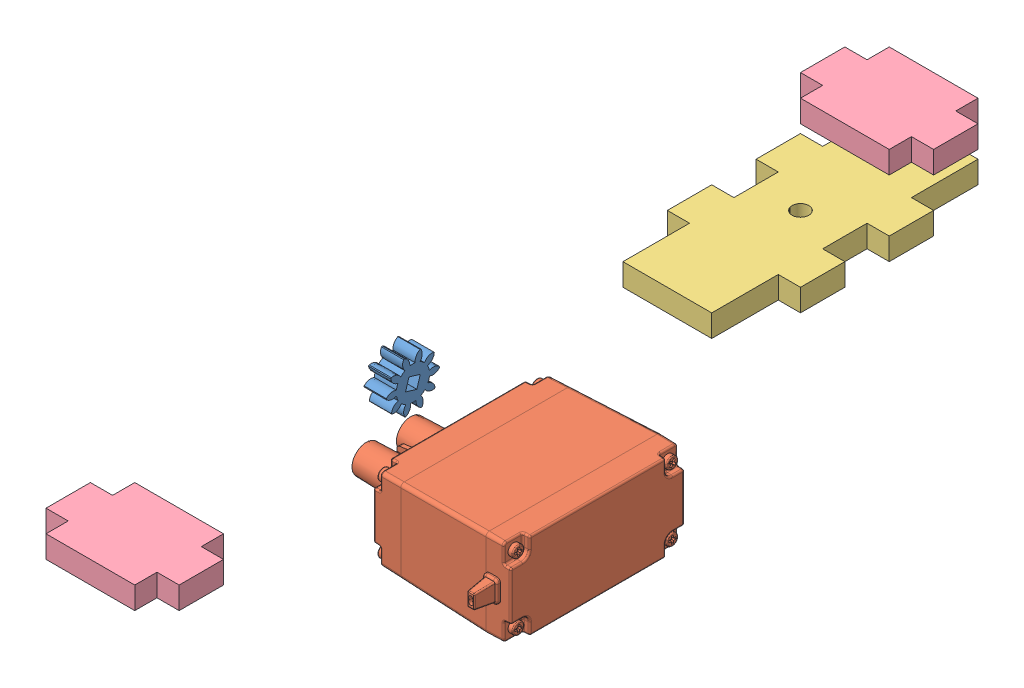
SolidWorks assembly Axis 2, configuration Default. Lengths in mm.
Overall size (105.18 50.55 254).
7 component instances, 5 part files, 17 mates.
Components (placement in the parent):
- spur gear_ai-1: spur gear_ai [Inch - Spur gear 20DP 10T 20PA 0.25"FW ---S10N3.0H2.0L0.1875N] at (-25.5488 56.17 -24.2712) x (1 0 0) z (0 0.958122 -0.28636) size (6.35 14.58 15.24)
- rack spur rectangular_ai-1: rack spur rectangular_ai [Inch - Rack-spur - rectangular 20DP 20PA 0.25"FW 1"PH 10L---SAll] at (-19.1988 24.474 55.3228) x (0 0 -1) z (1 0 0) size (254 26.67 6.35)
- 276-2177-1: 276-2177 [Default] at (40.8761 56.17 1.4288) x (0 0 -1) z (0 -1 0) size (56.4 55.81 25)
- Adapter Plate-1: Adapter Plate [Default] at (-38.2488 18.124 -147.8772) x (0 0 1) z (-1 0 0) size (76.2 6.35 38.1)
- rack spur rectangular_ai-2: rack spur rectangular_ai [Inch - Rack-spur - rectangular 20DP 20PA 0.25"FW 1"PH 10L---SAll] at (-50.9488 24.474 55.3228) x (0 0 -1) z (1 0 0) size (254 26.67 6.35)
- Rack Bridge-3: Rack Bridge [Default] at (-50.9488 33.237 48.9728) x (0 0 1) z (0 1 0) size (25.4 38.1 6.35)
- Rack Bridge-4: Rack Bridge [Default] at (-50.9488 33.237 -166.9272) x (0 0 1) z (0 1 0) size (25.4 38.1 6.35)
Mates (geometry in assembly coordinates):
- Coincident1: coincident aligned: plane of spur gear_ai-1 through (-19.1988 56.17 -24.2712) normal (1 0 0); plane of rack spur rectangular_ai-1 through (-19.1988 51.144 55.3228) normal (1 0 0)
- Parallel1: parallel anti-aligned: plane of rack spur rectangular_ai-1 through (-25.5488 24.474 55.3228) normal (0 -1 0); plane of assembly through (0 0 0) normal (0 1 0)
- RackPinionMate1: rack pinion = 12.7 mm: line of rack spur rectangular_ai-1 through (-25.5488 24.474 55.3228) axis (0 0 -1); circle of spur gear_ai-1
- Concentric1: concentric anti-aligned: circle of spur gear_ai-1; circle of 276-2177-1
- Distance3: distance = 0.2 mm anti-aligned: cylinder of spur gear_ai-1 through (-35.5488 56.17 -24.2712) axis (-1 0 0) radius 7.62; plane of rack spur rectangular_ai-1 through (-25.5488 48.35 -9.1095) normal (0 1 0)
- Coincident5: coincident anti-aligned: plane of rack spur rectangular_ai-1 through (-25.5488 24.474 55.3228) normal (0 -1 0); plane of Adapter Plate-1 through (-38.2488 24.474 -147.8772) normal (0 1 0)
- Coincident6: coincident anti-aligned: plane of rack spur rectangular_ai-1 through (-25.5488 51.144 55.3228) normal (-1 0 0); plane of Adapter Plate-1 through (-25.5488 24.474 -147.8772) normal (1 0 0)
- Coincident7: coincident anti-aligned: plane of rack spur rectangular_ai-1 through (-57.2988 18.124 -173.2772) normal (0 0 1); plane of Adapter Plate-1 through (-38.2488 24.474 -173.2772) normal (0 0 -1)
- Coincident8: coincident anti-aligned: plane of rack spur rectangular_ai-2 through (-50.9487 33.237 -173.2772) normal (0 1 0); plane of ? through (-31.8988 33.237 -245.1256) normal (0 -1 0)
- Coincident11: coincident anti-aligned: plane of rack spur rectangular_ai-2 through (-50.9488 51.144 55.3228) normal (1 0 0); plane of ? through (-50.9488 33.237 -245.1256) normal (-1 0 0)
- Coincident13: coincident anti-aligned: plane of Adapter Plate-1 through (-50.9488 24.474 -147.8772) normal (-1 0 0); plane of rack spur rectangular_ai-2 through (-50.9488 51.144 55.3228) normal (1 0 0)
- Coincident15: coincident anti-aligned: plane of rack spur rectangular_ai-1 through (-19.1987 33.237 -173.2772) normal (0 1 0); plane of Rack Bridge-3 through (-72.239 33.237 48.9728) normal (0 -1 0)
- Coincident16: coincident anti-aligned: plane of rack spur rectangular_ai-1 through (-19.1987 33.237 -173.2772) normal (0 1 0); plane of Rack Bridge-4 through (-50.9488 33.237 -166.9272) normal (0 -1 0)
- Coincident19: coincident anti-aligned: plane of rack spur rectangular_ai-2 through (-50.9487 33.237 -185.9772) normal (0 0 1); plane of Rack Bridge-4 through (-50.9488 39.587 -185.9772) normal (0 0 -1)
- Coincident20: coincident aligned: plane of rack spur rectangular_ai-2 through (-57.2988 51.144 55.3228) normal (-1 0 0); plane of Rack Bridge-4 through (-57.2988 39.587 -166.9272) normal (-1 0 0)
- Coincident21: coincident anti-aligned: plane of rack spur rectangular_ai-2 through (-50.9487 33.237 29.9228) normal (0 0 1); plane of Rack Bridge-3 through (-72.239 39.587 29.9228) normal (0 0 -1)
- Coincident22: coincident aligned: plane of rack spur rectangular_ai-2 through (-57.2988 51.144 55.3228) normal (-1 0 0); plane of Rack Bridge-3 through (-57.2988 39.587 48.9728) normal (-1 0 0)
